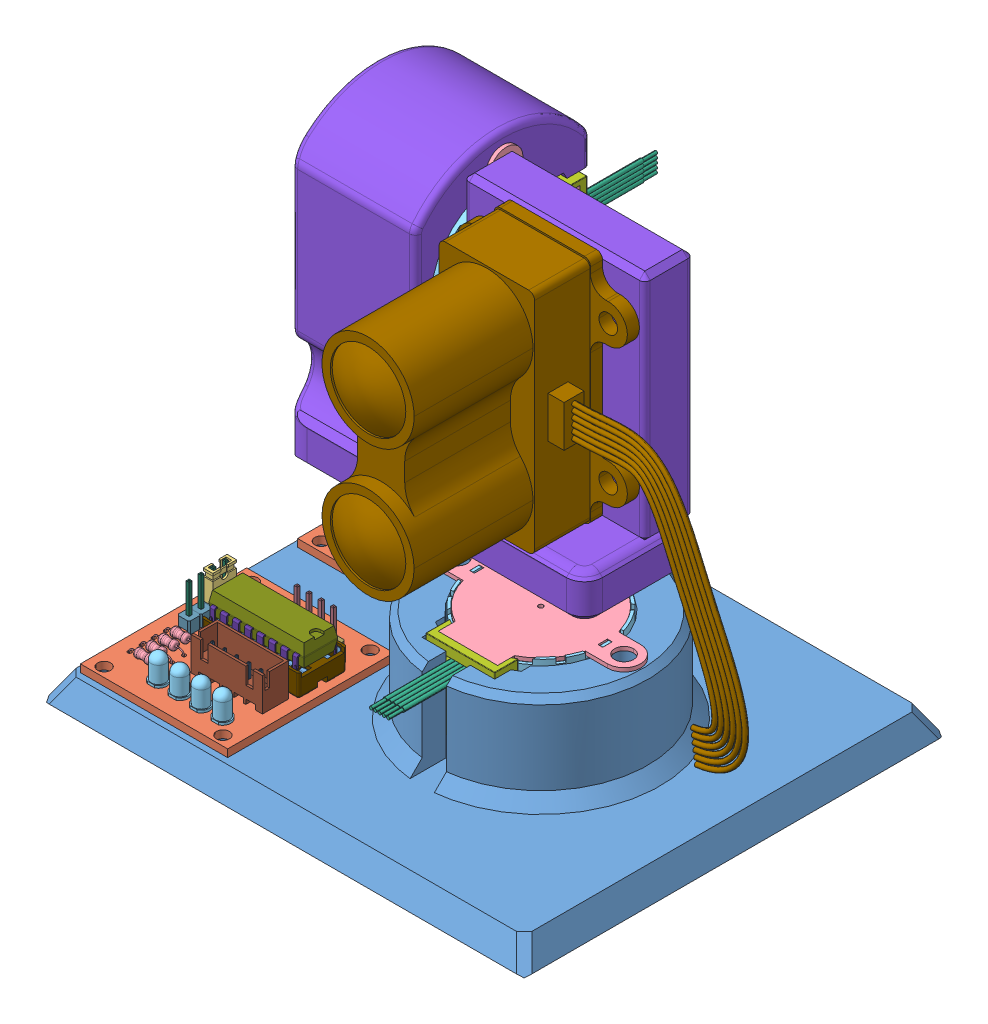
SolidWorks assembly LIDAR System Assembly, configuration Default. Lengths in mm.
Overall size (110.72 94.65 94.03).
121 component instances, 23 part files, 19 mates.
Components (placement in the parent):
- Housing base V2-1: Housing base V2 [Default] at (-26.636 1.1076 8.8595) size (101.63 25.78 88.93)
- 28BYJ-48_Stepper_Motor-1: 28BYJ-48_Stepper_Motor [Default] at (-26.636 13.1386 0.9595) x (-1 0 0) z (0 0 -1) size (42 29.25 47.99)
  - 28BYJ-48.STEP-1: 28BYJ-48.STEP [Default] at origin size (42 29.25 47.99)
    - 28BYJ-48-005.STEP-1: 28BYJ-48-005.STEP [Default] at origin size (5 18 5)
    - 28BYJ-48-003.STEP-1: 28BYJ-48-003.STEP [Default] at (0 -0.5 0) size (7.6 10 7.6)
    - 28BYJ-48-002.STEP-1: 28BYJ-48-002.STEP [Default] at (0 7.4 -7.9) size (42 2.3 29.5)
    - 28BYJ-48-001.STEP-1: 28BYJ-48-001.STEP [Default] at (0 -10.6 -7.9) size (28.73 19.65 28.03)
    - 28BYJ-48-007.STEP-1: 28BYJ-48-007.STEP [Default] at (0 5.7 -23.8765) x (-1 0 0) z (0 0 -1) size (4.5 0.9 18)
    - 28BYJ-48-006.STEP-1: 28BYJ-48-006.STEP [Default] at (0 -0.05 -24.8765) x (0 0 1) z (-1 0 0) size (6.01 17.5 17.49)
- Mount to bottom motor-1: Mount to bottom motor [Default] at (-29.4996 25.1386 6.467) x (-1 0 0) z (0 0 -1) size (71.43 64.29 40.22)
- Garmin_LiDAR_Lite-V3-1: Garmin_LiDAR_Lite-V3 [Default] at (-26.598 65.1055 8.5795) x (0 -1 0) z (-1 0 0) size (74.47 42.96 67.95)
- ULN2003 Stepper Driver-2: ULN2003 Stepper Driver [Default] at (-67.7145 1.1076 31.7137) x (1 0 0) z (0 1 0) size (31 35 12.67)
  - ULN2003 Stepper Driver.stp-1: ULN2003 Stepper Driver.stp [Default] at origin size (31 35 12.67)
    - motor_connector.stp-1: motor_connector.stp [Default] at (-15.5 -17.5 0.2) size (15 5.5 9.89)
      - conn_lead.stp-1: conn_lead.stp [Default] at origin size (0.4 0.4 8.89)
      - conn_lead.stp-2: conn_lead.stp [Default] at (-2.54 0 0) size (0.4 0.4 8.89)
      - conn_lead.stp-3: conn_lead.stp [Default] at (-5.08 0 0) size (0.4 0.4 8.89)
      - conn_lead.stp-4: conn_lead.stp [Default] at (-7.62 0 0) size (0.4 0.4 8.89)
      - conn_lead.stp-5: conn_lead.stp [Default] at (-10.16 0 0) size (0.4 0.4 8.89)
      - motor_connector-0.stp-1: motor_connector-0.stp [Default] at origin size (15 5.5 7)
    - Pin Header 1x4 TH Pitch 2.54mm v2.stp-1: Pin Header 1x4 TH Pitch 2.54mm v2.stp [Default] at (1.6199 11.0001 1.46) size (10.16 2.54 11.43)
      - asm_pin.stp-1: asm_pin.stp [Default] at origin size (2.54 2.54 11.43)
        - spacer.stp-1: spacer.stp [Default] at origin size (2.54 2.54 2.54)
        - pin.stp-1: pin.stp [Default] at origin size (0.64 0.64 11.43)
      - asm_pin_1.stp-1: asm_pin_1.stp [Default] at (2.54 0 0) size (2.54 2.54 11.43)
        - spacer.stp-1: spacer.stp [Default] at origin size (2.54 2.54 2.54)
        - pin.stp-1: pin.stp [Default] at origin size (0.64 0.64 11.43)
      - asm_pin_2.stp-1: asm_pin_2.stp [Default] at (5.08 0 0) size (2.54 2.54 11.43)
        - spacer.stp-1: spacer.stp [Default] at origin size (2.54 2.54 2.54)
        - pin.stp-1: pin.stp [Default] at origin size (0.64 0.64 11.43)
      - asm_pin_3.stp-1: asm_pin_3.stp [Default] at (7.62 0 0) size (2.54 2.54 11.43)
        - spacer.stp-1: spacer.stp [Default] at origin size (2.54 2.54 2.54)
        - pin.stp-1: pin.stp [Default] at origin size (0.64 0.64 11.43)
    - Pin Header 1x4 TH Pitch 2.54mm v2 (1).stp-1: Pin Header 1x4 TH Pitch 2.54mm v2 (1).stp [Default] at (-10.4999 8.0001 1.5722) x (0 -1 0) z (0 0 1) size (10.16 2.54 11.43)
      - asm_pin (1).stp-1: asm_pin (1).stp [Default] at origin size (2.54 2.54 11.43)
        - spacer (1).stp-1: spacer (1).stp [Default] at origin size (2.54 2.54 2.54)
        - pin (1).stp-1: pin (1).stp [Default] at origin size (0.64 0.64 11.43)
      - asm_pin (1)_1.stp-1: asm_pin (1)_1.stp [Default] at (2.54 0 0) size (2.54 2.54 11.43)
        - spacer (1).stp-1: spacer (1).stp [Default] at origin size (2.54 2.54 2.54)
        - pin (1).stp-1: pin (1).stp [Default] at origin size (0.64 0.64 11.43)
      - asm_pin (1)_2.stp-1: asm_pin (1)_2.stp [Default] at (5.08 0 0) size (2.54 2.54 11.43)
        - spacer (1).stp-1: spacer (1).stp [Default] at origin size (2.54 2.54 2.54)
        - pin (1).stp-1: pin (1).stp [Default] at origin size (0.64 0.64 11.43)
      - asm_pin (1)_3.stp-1: asm_pin (1)_3.stp [Default] at (7.62 0 0) size (2.54 2.54 11.43)
        - spacer (1).stp-1: spacer (1).stp [Default] at origin size (2.54 2.54 2.54)
        - pin (1).stp-1: pin (1).stp [Default] at origin size (0.64 0.64 11.43)
    - dip16 v2.stp-1: dip16 v2.stp [Default] at (4.1 3.5 6) x (0 1 0) z (0 0 1) size (8.74 20 8.41)
      - package.stp-1: package.stp [Default] at origin size (7.1 20 4.6)
      - lead.stp-1: lead.stp [Default] at origin size (8.74 18.4 6.23)
    - dip16_socket v4.stp-1: dip16_socket v4.stp [Default] at (4.1 3.7 1.6) x (-1 0 0) z (0 0 1) size (20.49 10.21 8.2)
      - housing.stp-1: housing.stp [Default] at origin size (20.49 10.21 5.04)
      - pins.stp-1: pins.stp [Default] at origin size (19.03 9.24 7.72)
    - pcb.stp-1: pcb.stp [Default] at origin size (31 35 1.6)
    - jumper_connector.stp-1: jumper_connector.stp [Default] at (-15.35 -12.425 0) size (2 5 6)
    - r205.stp-1: r205.stp [Default] at (-15.3 -2.6 0) size (6.69 1.8 3.9)
    - r205.stp-2: r205.stp [Default] at (-15.3 -5.14 0) size (6.69 1.8 3.9)
    - r205.stp-3: r205.stp [Default] at (-15.3 -7.68 0) size (6.69 1.8 3.9)
    - r205.stp-4: r205.stp [Default] at (-15.3 -10.22 0) size (6.69 1.8 3.9)
    - LED 3mm.stp-1: LED 3mm.stp [Default] at (-3.9107 -12.6768 1.7661) x (0 -1 0) z (-1 0 0) size (3.33 7.5 3.5)
    - LED 3mm.stp-2: LED 3mm.stp [Default] at (0.5893 -12.6768 1.7661) x (0 -1 0) z (-1 0 0) size (3.33 7.5 3.5)
    - LED 3mm.stp-3: LED 3mm.stp [Default] at (5.0893 -12.6768 1.7661) x (0 -1 0) z (-1 0 0) size (3.33 7.5 3.5)
    - LED 3mm.stp-4: LED 3mm.stp [Default] at (9.5893 -12.6768 1.7661) x (0 -1 0) z (-1 0 0) size (3.33 7.5 3.5)
- ULN2003 Stepper Driver-4: ULN2003 Stepper Driver [Default] at (-67.7145 1.1076 -13.9948) x (-1 0 0) z (0 1 0) size (31 35 12.67)
  - ULN2003 Stepper Driver.stp-1: ULN2003 Stepper Driver.stp [Default] at origin size (31 35 12.67)
    - motor_connector.stp-1: motor_connector.stp [Default] at (-15.5 -17.5 0.2) size (15 5.5 9.89)
      - conn_lead.stp-1: conn_lead.stp [Default] at origin size (0.4 0.4 8.89)
      - conn_lead.stp-2: conn_lead.stp [Default] at (-2.54 0 0) size (0.4 0.4 8.89)
      - conn_lead.stp-3: conn_lead.stp [Default] at (-5.08 0 0) size (0.4 0.4 8.89)
      - conn_lead.stp-4: conn_lead.stp [Default] at (-7.62 0 0) size (0.4 0.4 8.89)
      - conn_lead.stp-5: conn_lead.stp [Default] at (-10.16 0 0) size (0.4 0.4 8.89)
      - motor_connector-0.stp-1: motor_connector-0.stp [Default] at origin size (15 5.5 7)
    - Pin Header 1x4 TH Pitch 2.54mm v2.stp-1: Pin Header 1x4 TH Pitch 2.54mm v2.stp [Default] at (1.6199 11.0001 1.46) size (10.16 2.54 11.43)
      - asm_pin.stp-1: asm_pin.stp [Default] at origin size (2.54 2.54 11.43)
        - spacer.stp-1: spacer.stp [Default] at origin size (2.54 2.54 2.54)
        - pin.stp-1: pin.stp [Default] at origin size (0.64 0.64 11.43)
      - asm_pin_1.stp-1: asm_pin_1.stp [Default] at (2.54 0 0) size (2.54 2.54 11.43)
        - spacer.stp-1: spacer.stp [Default] at origin size (2.54 2.54 2.54)
        - pin.stp-1: pin.stp [Default] at origin size (0.64 0.64 11.43)
      - asm_pin_2.stp-1: asm_pin_2.stp [Default] at (5.08 0 0) size (2.54 2.54 11.43)
        - spacer.stp-1: spacer.stp [Default] at origin size (2.54 2.54 2.54)
        - pin.stp-1: pin.stp [Default] at origin size (0.64 0.64 11.43)
      - asm_pin_3.stp-1: asm_pin_3.stp [Default] at (7.62 0 0) size (2.54 2.54 11.43)
        - spacer.stp-1: spacer.stp [Default] at origin size (2.54 2.54 2.54)
        - pin.stp-1: pin.stp [Default] at origin size (0.64 0.64 11.43)
    - Pin Header 1x4 TH Pitch 2.54mm v2 (1).stp-1: Pin Header 1x4 TH Pitch 2.54mm v2 (1).stp [Default] at (-10.4999 8.0001 1.5722) x (0 -1 0) z (0 0 1) size (10.16 2.54 11.43)
      - asm_pin (1).stp-1: asm_pin (1).stp [Default] at origin size (2.54 2.54 11.43)
        - spacer (1).stp-1: spacer (1).stp [Default] at origin size (2.54 2.54 2.54)
        - pin (1).stp-1: pin (1).stp [Default] at origin size (0.64 0.64 11.43)
      - asm_pin (1)_1.stp-1: asm_pin (1)_1.stp [Default] at (2.54 0 0) size (2.54 2.54 11.43)
        - spacer (1).stp-1: spacer (1).stp [Default] at origin size (2.54 2.54 2.54)
        - pin (1).stp-1: pin (1).stp [Default] at origin size (0.64 0.64 11.43)
      - asm_pin (1)_2.stp-1: asm_pin (1)_2.stp [Default] at (5.08 0 0) size (2.54 2.54 11.43)
        - spacer (1).stp-1: spacer (1).stp [Default] at origin size (2.54 2.54 2.54)
        - pin (1).stp-1: pin (1).stp [Default] at origin size (0.64 0.64 11.43)
      - asm_pin (1)_3.stp-1: asm_pin (1)_3.stp [Default] at (7.62 0 0) size (2.54 2.54 11.43)
        - spacer (1).stp-1: spacer (1).stp [Default] at origin size (2.54 2.54 2.54)
        - pin (1).stp-1: pin (1).stp [Default] at origin size (0.64 0.64 11.43)
    - dip16 v2.stp-1: dip16 v2.stp [Default] at (4.1 3.5 6) x (0 1 0) z (0 0 1) size (8.74 20 8.41)
      - package.stp-1: package.stp [Default] at origin size (7.1 20 4.6)
      - lead.stp-1: lead.stp [Default] at origin size (8.74 18.4 6.23)
    - dip16_socket v4.stp-1: dip16_socket v4.stp [Default] at (4.1 3.7 1.6) x (-1 0 0) z (0 0 1) size (20.49 10.21 8.2)
      - housing.stp-1: housing.stp [Default] at origin size (20.49 10.21 5.04)
      - pins.stp-1: pins.stp [Default] at origin size (19.03 9.24 7.72)
    - pcb.stp-1: pcb.stp [Default] at origin size (31 35 1.6)
    - jumper_connector.stp-1: jumper_connector.stp [Default] at (-15.35 -12.425 0) size (2 5 6)
    - r205.stp-1: r205.stp [Default] at (-15.3 -2.6 0) size (6.69 1.8 3.9)
    - r205.stp-2: r205.stp [Default] at (-15.3 -5.14 0) size (6.69 1.8 3.9)
    - r205.stp-3: r205.stp [Default] at (-15.3 -7.68 0) size (6.69 1.8 3.9)
    - r205.stp-4: r205.stp [Default] at (-15.3 -10.22 0) size (6.69 1.8 3.9)
    - LED 3mm.stp-1: LED 3mm.stp [Default] at (-3.9107 -12.6768 1.7661) x (0 -1 0) z (-1 0 0) size (3.33 7.5 3.5)
    - LED 3mm.stp-2: LED 3mm.stp [Default] at (0.5893 -12.6768 1.7661) x (0 -1 0) z (-1 0 0) size (3.33 7.5 3.5)
    - LED 3mm.stp-3: LED 3mm.stp [Default] at (5.0893 -12.6768 1.7661) x (0 -1 0) z (-1 0 0) size (3.33 7.5 3.5)
    - LED 3mm.stp-4: LED 3mm.stp [Default] at (9.5893 -12.6768 1.7661) x (0 -1 0) z (-1 0 0) size (3.33 7.5 3.5)
- 28BYJ-48_Stepper_Motor-4: 28BYJ-48_Stepper_Motor [Default] at (-57.686 64.8116 1.1735) x (0 -1 0) z (0 0 1) size (42 29.25 47.99)
  - 28BYJ-48.STEP-1: 28BYJ-48.STEP [Default] at origin size (42 29.25 47.99)
    - 28BYJ-48-005.STEP-1: 28BYJ-48-005.STEP [Default] at origin size (5 18 5)
    - 28BYJ-48-003.STEP-1: 28BYJ-48-003.STEP [Default] at (0 -0.5 0) size (7.6 10 7.6)
    - 28BYJ-48-002.STEP-1: 28BYJ-48-002.STEP [Default] at (0 7.4 -7.9) size (42 2.3 29.5)
    - 28BYJ-48-001.STEP-1: 28BYJ-48-001.STEP [Default] at (0 -10.6 -7.9) size (28.73 19.65 28.03)
    - 28BYJ-48-007.STEP-1: 28BYJ-48-007.STEP [Default] at (0 5.7 -23.8765) x (-1 0 0) z (0 0 -1) size (4.5 0.9 18)
    - 28BYJ-48-006.STEP-1: 28BYJ-48-006.STEP [Default] at (0 -0.05 -24.8765) x (0 0 1) z (-1 0 0) size (6.01 17.5 17.49)
Mates (geometry in assembly coordinates):
- Coincident1: coincident: plane of Housing base V2-1 through (-26.636 20.5386 8.8595) normal (0 1 0); plane of 28BYJ-48_Stepper_Motor-1/28BYJ-48.STEP-1/28BYJ-48-002.STEP-1 through (-26.636 20.5386 8.8595) normal (0 -1 0)
- Parallel1: parallel: plane of 28BYJ-48_Stepper_Motor-1/28BYJ-48.STEP-1/28BYJ-48-005.STEP-1 through (-28.111 25.1386 2.978) normal (-1 0 0); plane of Mount to bottom motor-1 through (-24.907 34.0286 6.467) normal (-1 0 0)
- Concentric1: concentric: cylinder of Housing base V2-1 through (-26.636 20.5386 8.8595) axis (0 -1 0) radius 14.3193; cylinder of 28BYJ-48_Stepper_Motor-1/28BYJ-48.STEP-1/28BYJ-48-001.STEP-1 through (-26.636 1.9386 8.8595) axis (0 1 0) radius 14
- Parallel2: parallel: plane of Housing base V2-1 through (-34.2705 -20.4093 22.8133) normal (1 0 0); plane of 28BYJ-48_Stepper_Motor-1/28BYJ-48.STEP-1/28BYJ-48-006.STEP-1 through (-33.886 4.8386 20.836) normal (-1 0 0)
- Coincident13: coincident: plane of Housing base V2-1 through (-26.636 1.1076 8.8595) normal (0 1 0); plane of ULN2003 Stepper Driver-2/ULN2003 Stepper Driver.stp-1/pcb.stp-1 through (-67.7145 1.1076 31.7137) normal (0 -1 0)
- Distance7: distance = 1.27 mm: line of ULN2003 Stepper Driver-2/ULN2003 Stepper Driver.stp-1/pcb.stp-1 through (-52.2145 1.1076 49.2137) axis (-1 0 0); line of Housing base V2-1 through (9.8142 1.1076 50.4837) axis (-1 0 0)
- Distance8: distance = 1.27 mm: line of ULN2003 Stepper Driver-2/ULN2003 Stepper Driver.stp-1/pcb.stp-1 through (-83.2145 1.1076 49.2137) axis (0 0 -1); line of Housing base V2-1 through (-84.4845 1.1076 48.8339) axis (0 0 -1)
- Coincident16: coincident: plane of Housing base V2-1 through (-26.636 1.1076 8.8595) normal (0 1 0); plane of ULN2003 Stepper Driver-4/ULN2003 Stepper Driver.stp-1/pcb.stp-1 through (-67.7145 1.1076 -13.9948) normal (0 -1 0)
- Distance11: distance = 1.27 mm: line of ULN2003 Stepper Driver-4/ULN2003 Stepper Driver.stp-1/pcb.stp-1 through (-83.2145 1.1076 3.5052) axis (0 0 -1); line of Housing base V2-1 through (-84.4845 1.1076 48.8339) axis (0 0 -1)
- Distance12: distance = 1.27 mm: line of Housing base V2-1 through (-82.8347 1.1076 -32.7648) axis (1 0 0); line of ULN2003 Stepper Driver-4/ULN2003 Stepper Driver.stp-1/pcb.stp-1 through (-83.2145 1.1076 -31.4948) axis (1 0 0)
- Tangent15: tangent: plane of Mount to bottom motor-1 through (-44.543 89.4006 6.0395) normal (0 0 1); face of Garmin_LiDAR_Lite-V3-1
- Tangent16: tangent: plane of Mount to bottom motor-1 through (-44.543 89.4006 4.8965) normal (0 1 0); face of Garmin_LiDAR_Lite-V3-1
- Distance15: distance = 0.254 mm: plane of Mount to bottom motor-1 through (-28.365 34.0286 6.467) normal (1 0 0); plane of 28BYJ-48_Stepper_Motor-1/28BYJ-48.STEP-1/28BYJ-48-005.STEP-1 through (-28.111 25.1386 2.978) normal (-1 0 0)
- Distance16: distance = 0.254 mm: line of 28BYJ-48_Stepper_Motor-1/28BYJ-48.STEP-1/28BYJ-48-005.STEP-1 through (-26.636 30.7386 -1.5405) axis (0 -1 0); plane of Mount to bottom motor-1 through (-29.4996 34.0286 -1.7945) normal (0 0 1)
- Coincident23: coincident: plane of Mount to bottom motor-1 through (-45.686 89.4006 4.8965) normal (-1 0 0); plane of 28BYJ-48_Stepper_Motor-4/28BYJ-48.STEP-1/28BYJ-48-005.STEP-1 through (-45.686 64.8116 1.1735) normal (1 0 0)
- Parallel4: parallel: plane of Mount to bottom motor-1 through (-38.066 63.2386 -1.5805) normal (0 1 0); plane of 28BYJ-48_Stepper_Motor-4/28BYJ-48.STEP-1/28BYJ-48-005.STEP-1 through (-45.686 66.2866 -0.845) normal (0 1 0)
- Distance17: distance = 0.254 mm: plane of Mount to bottom motor-1 through (-38.066 66.5406 -1.5805) normal (0 0 1); line of 28BYJ-48_Stepper_Motor-4/28BYJ-48.STEP-1/28BYJ-48-005.STEP-1 through (-40.086 64.8116 -1.3265) axis (-1 0 0)
- Distance18: distance = 0.254 mm: plane of 28BYJ-48_Stepper_Motor-4/28BYJ-48.STEP-1/28BYJ-48-005.STEP-1 through (-45.686 66.2866 -0.845) normal (0 1 0); plane of Mount to bottom motor-1 through (-38.066 66.5406 -1.5805) normal (0 -1 0)
- Coincident25: coincident: plane of 28BYJ-48_Stepper_Motor-1/28BYJ-48.STEP-1/28BYJ-48-005.STEP-1 through (-26.636 25.1386 0.9595) normal (0 1 0); plane of Mount to bottom motor-1 through (-29.4996 25.1386 6.467) normal (0 -1 0)
